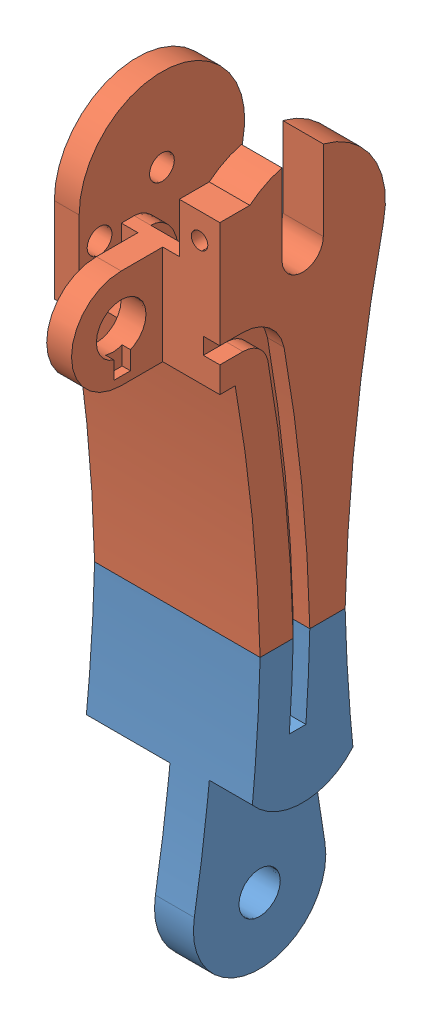
SolidWorks assembly Assem1, configuration Default. Lengths in mm.
Overall size (20 88 31.02).
2 component instances, 2 part files, 3 mates.
Components (placement in the parent):
- digit with pot_shortened_base-1: digit with pot_shortened_base [Default] at (2.9021 60.4743 33.7593) size (20 37.78 16)
- digit with pot_shortened_top-1: digit with pot_shortened_top [Default] at (2.9021 50.4743 33.7593) size (20 50.22 31.02)
Mates (geometry in assembly coordinates):
- Coincident4: coincident: plane of digit with pot_shortened_base-1 through (2.9021 32.5194 43.0641) normal (0 1 0); plane of digit with pot_shortened_top-1 through (2.9021 32.5194 11.1217) normal (0 -1 0)
- Distance3: distance = 0 mm: plane of digit with pot_shortened_top-1 through (2.9021 50.1319 136.2956) normal (-1 0 0); plane of digit with pot_shortened_base-1 through (2.9021 60.1319 136.2956) normal (-1 0 0)
- Coincident9: coincident anti-aligned: line of digit with pot_shortened_base-1 through (22.9021 32.5194 38.8943) axis (-1 0 0); line of digit with pot_shortened_top-1 through (2.9021 32.5194 38.8943) axis (1 0 0)
